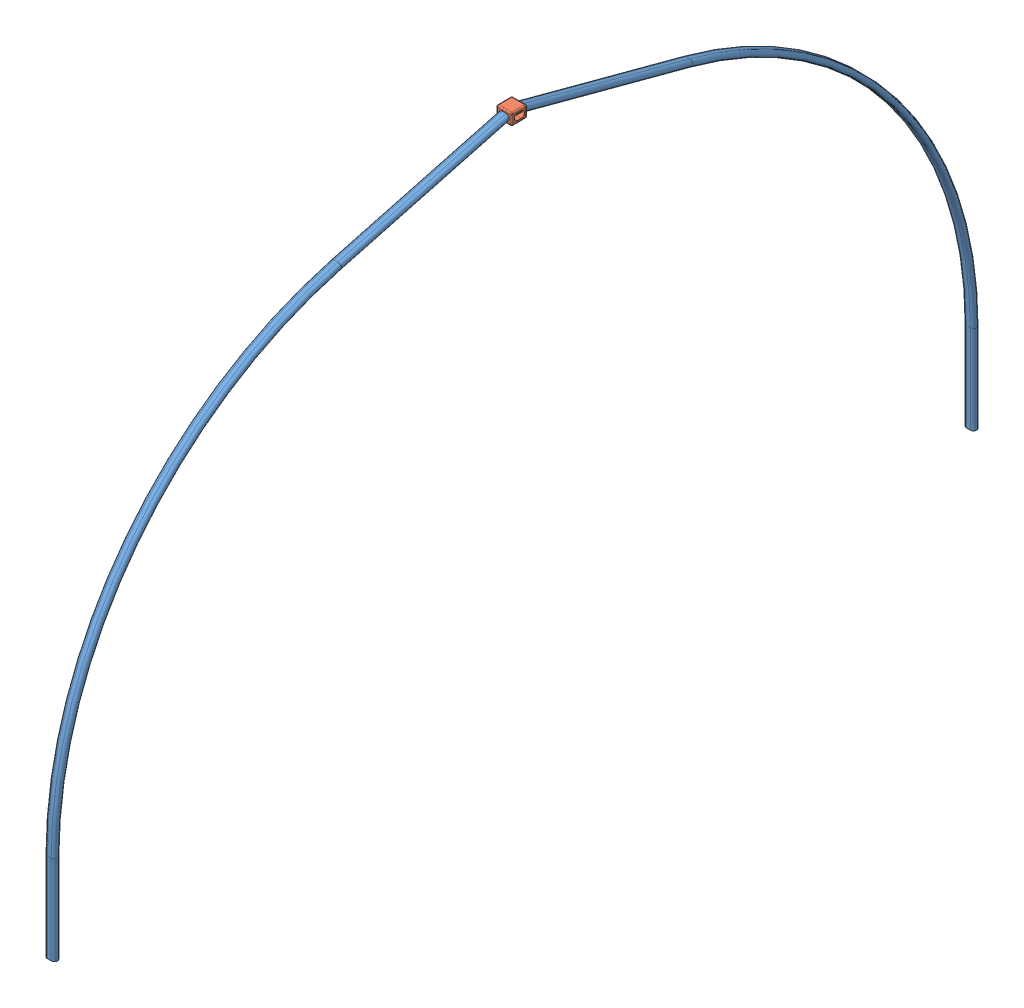
SolidWorks assembly Connector Subtracted, configuration Default. Lengths in mm.
Overall size (152.4 5067.82 9207.5).
2 component instances, 2 part files, 3 mates.
Components (placement in the parent):
- Arch-1: Arch [Default] at (125.3762 2242.3477 10556.0095) size (101.6 5052.07 9207.5)
- ConnectorV2-2: ConnectorV2 [Default] at (68.2262 7252.1131 5986.1967) x (0 0.011975 -0.999928) z (0 -0.999928 -0.011975) size (152.4 152.4 114.3)
Mates (geometry in assembly coordinates):
- Coincident5: coincident: point of Arch-1
- Coincident6: coincident: unknown of Arch-1
- Coincident8: coincident: unknown of Arch-1
